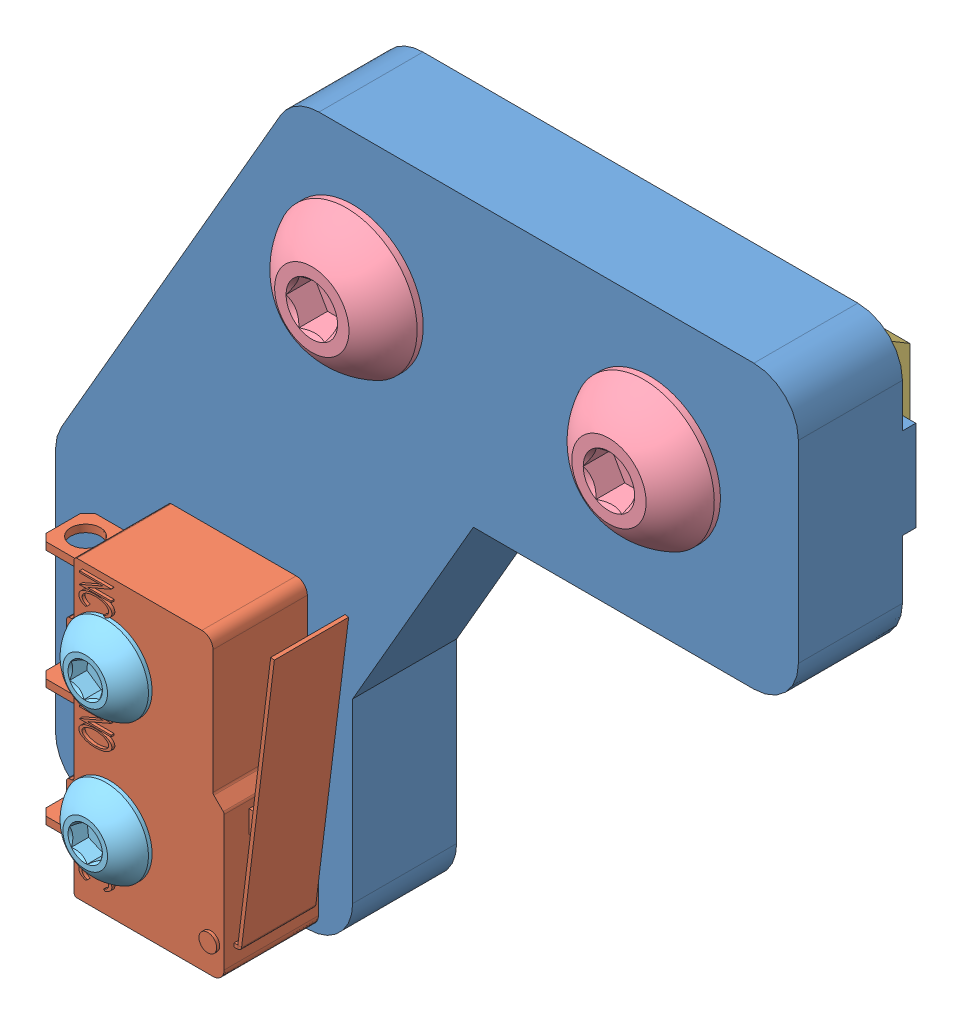
SolidWorks assembly X_Axis_Endstop, configuration Default. Lengths in mm.
Overall size (50 48 20.62).
8 component instances, 5 part files, 19 mates.
Components (placement in the parent):
- X Endstop Mount-1: X Endstop Mount [Default] at origin size (50 48 7.9)
- Micro Switch Button-1: Micro Switch Button [Default] at (12.4 9.4 10.175) x (0 0 1) z (0 1 0) size (6.75 16.71 19.86)
- HNTTSN5-5-1: HNTTSN5-5 [Default] at (20 39 -1.2) x (0 0 1) z (1 0 0) size (4.3 10 10)
- HNTTSN5-5-2: HNTTSN5-5 [Default] at (40 39 -1.2) x (0 0 1) z (-1 0 0) size (4.3 10 10)
- 5mmX12mm_Buttonhead(McMaster_92095A210)-1: 5mmX12mm_Buttonhead(McMaster_92095A210) [92095A210] at (40 39 9.75) x (0.866025 0.5 0) z (0 0 1) size (9.5 9.5 15.22)
- 5mmX12mm_Buttonhead(McMaster_92095A210)-2: 5mmX12mm_Buttonhead(McMaster_92095A210) [92095A210] at (20 39 9.75) x (0.866025 0.5 0) z (0 0 1) size (9.5 9.5 15.22)
- 3mmX12mm_Buttonhead(McMaster_92095A183)-1: 3mmX12mm_Buttonhead(McMaster_92095A183) [92095A183] at (10 5.5 15) x (0.402198 0.915553 0) z (0 0 1) size (5.7 5.7 13.97)
- 3mmX12mm_Buttonhead(McMaster_92095A183)-2: 3mmX12mm_Buttonhead(McMaster_92095A183) [92095A183] at (10 15 15) x (0.435949 -0.899971 0) z (0 0 1) size (5.7 5.7 13.97)
Mates (geometry in assembly coordinates):
- Concentric1: concentric anti-aligned: cylinder of X Endstop Mount-1 through (20 39 7) axis (0 0 -1) radius 2.5; cylinder of 5mmX12mm_Buttonhead(McMaster_92095A210)-2 through (20 39 9.75) axis (0 0 1) radius 4.75
- Concentric2: concentric anti-aligned: cylinder of X Endstop Mount-1 through (40 39 7) axis (0 0 -1) radius 2.5; cylinder of 5mmX12mm_Buttonhead(McMaster_92095A210)-1 through (40 39 9.75) axis (0 0 1) radius 4.75
- Coincident1: coincident anti-aligned: plane of X Endstop Mount-1 through (3 19.4833 7) normal (0 0 1); plane of 5mmX12mm_Buttonhead(McMaster_92095A210)-2 through (22.375 34.8864 7) normal (0 0 -1)
- Coincident2: coincident anti-aligned: plane of X Endstop Mount-1 through (3 19.4833 7) normal (0 0 1); plane of 5mmX12mm_Buttonhead(McMaster_92095A210)-1 through (42.375 34.8864 7) normal (0 0 -1)
- Concentric3: concentric anti-aligned: cylinder of HNTTSN5-5-2 through (40 39 -1.2) axis (0 0 -1) radius 2.067; cylinder of 5mmX12mm_Buttonhead(McMaster_92095A210)-1 through (40 39 9.75) axis (0 0 1) radius 4.75
- Concentric4: concentric anti-aligned: cylinder of HNTTSN5-5-1 through (20 39 -1.2) axis (0 0 -1) radius 2.067; cylinder of 5mmX12mm_Buttonhead(McMaster_92095A210)-2 through (20 39 9.75) axis (0 0 1) radius 4.75
- Distance1: distance = 2 mm anti-aligned: plane of X Endstop Mount-1 through (3 19.4833 0) normal (0 0 -1); plane of HNTTSN5-5-1 through (25 36.1 -2) normal (0 0 1)
- Distance2: distance = 2 mm anti-aligned: plane of X Endstop Mount-1 through (3 19.4833 0) normal (0 0 -1); plane of HNTTSN5-5-2 through (35 34 -2) normal (0 0 1)
- Parallel1: parallel aligned: plane of X Endstop Mount-1 through (50 32 7) normal (1 0 0); plane of HNTTSN5-5-2 through (45 39 -1.2) normal (1 0 0)
- Parallel2: parallel aligned: plane of X Endstop Mount-1 through (50 32 7) normal (1 0 0); plane of HNTTSN5-5-1 through (25 39 -1.2) normal (1 0 0)
- Concentric5: concentric anti-aligned: cylinder of X Endstop Mount-1 through (10 15 7) axis (0 0 -1) radius 1.1; cylinder of Micro Switch Button-1 through (10 15 7) axis (0 0 1) radius 1.35
- Coincident7: coincident anti-aligned: plane of X Endstop Mount-1 through (3 19.4833 7) normal (0 0 1); plane of Micro Switch Button-1 through (7.8 0.6 7) normal (0 0 -1)
- Parallel3: parallel aligned: plane of X Endstop Mount-1 through (3 0 7) normal (0 -1 0); plane of Micro Switch Button-1 through (16.95 0.4 13.35) normal (0 -1 0)
- Concentric6: concentric aligned: cylinder of Micro Switch Button-1 through (10 15 7) axis (0 0 1) radius 1.35; cylinder of 3mmX12mm_Buttonhead(McMaster_92095A183)-2 through (10 15 15) axis (0 0 1) radius 2.85
- Concentric7: concentric aligned: cylinder of Micro Switch Button-1 through (10 5.5 7) axis (0 0 1) radius 1.35; cylinder of 3mmX12mm_Buttonhead(McMaster_92095A183)-1 through (10 5.5 15) axis (0 0 1) radius 2.85
- Coincident9: coincident anti-aligned: plane of Micro Switch Button-1 through (7.8 0.6 13.35) normal (0 0 1); plane of 3mmX12mm_Buttonhead(McMaster_92095A183)-2 through (7.4351 13.7575 13.35) normal (0 0 -1)
- Coincident10: coincident anti-aligned: plane of Micro Switch Button-1 through (7.8 0.6 13.35) normal (0 0 1); plane of 3mmX12mm_Buttonhead(McMaster_92095A183)-1 through (12.6093 4.3537 13.35) normal (0 0 -1)
- Parallel4: parallel anti-aligned: plane of X Endstop Mount-1 through (47 48 7) normal (0 1 0); plane of 5mmX12mm_Buttonhead(McMaster_92095A210)-2 through (20.866 40.5 7.825) normal (0 -1 0)
- Parallel5: parallel anti-aligned: plane of X Endstop Mount-1 through (47 48 7) normal (0 1 0); plane of 5mmX12mm_Buttonhead(McMaster_92095A210)-1 through (40.866 40.5 7.825) normal (0 -1 0)
